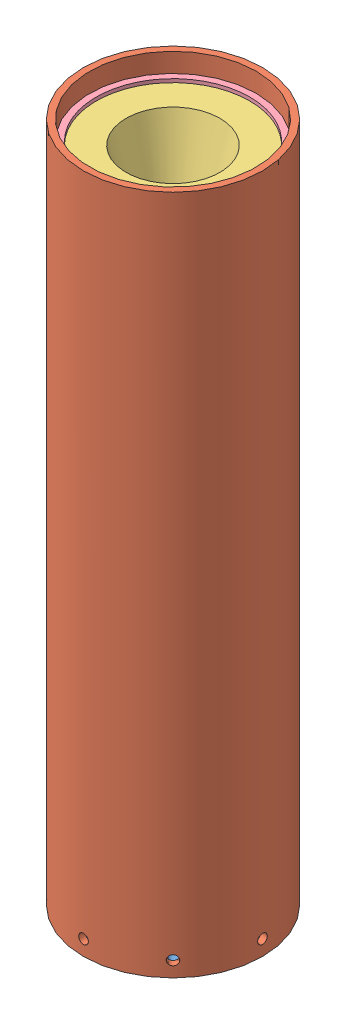
SolidWorks assembly Assem2, configuration Default. Lengths in mm.
Overall size (116.74 342.84 116.74).
4 component instances, 4 part files, 6 mates.
Components (placement in the parent):
- Injector_rev2-1: Injector_rev2 [Default] at (0 39.37 0) x (-0.707107 0 -0.707107) z (-0.707107 0 0.707107) size (82.55 44.64 82.55)
- Engine Casing-1: Engine Casing [Default] at origin size (88.9 337.57 88.9)
- Nozzle_rev2-1: Nozzle_rev2 [Default] at (0 326.3138 0) x (-0.78802 0 -0.615649) z (-0.615649 0 0.78802) size (82.55 76.59 82.55)
- Snap Ring-1: Snap Ring [Default] at (0 326.3138 0) size (83.82 1.73 83.82)
Mates (geometry in assembly coordinates):
- Concentric1: concentric anti-aligned: cylinder of Injector_rev2-1 through (0 94.37 0) axis (0 1 0) radius 41.275; cylinder of Engine Casing-1 through (0 0 0) axis (0 -1 0) radius 41.275
- Concentric2: concentric aligned: cylinder of Injector_rev2-1 through (41.275 7.62 0) axis (1 0 0) radius 2.3813; cylinder of Engine Casing-1 through (44.45 7.62 0) axis (1 0 0) radius 2.3813
- Coincident1: coincident anti-aligned: plane of Engine Casing-1 through (0 326.3138 0) normal (0 1 0); plane of Snap Ring-1 through (0 326.3138 0) normal (0 -1 0)
- Concentric4: concentric aligned: cylinder of Engine Casing-1 through (0 0 0) axis (0 -1 0) radius 42.5958; cylinder of Snap Ring-1 through (0 328.041 0) axis (0 -1 0) radius 41.91
- Concentric5: concentric anti-aligned: cylinder of Engine Casing-1 through (0 0 0) axis (0 -1 0) radius 41.275; cylinder of Nozzle_rev2-1 through (0 315.1099 0) axis (0 1 0) radius 41.275
- Coincident2: coincident anti-aligned: plane of Nozzle_rev2-1 through (-32.5255 326.3138 -25.4109) normal (0 1 0); plane of Snap Ring-1 through (0 326.3138 0) normal (0 -1 0)
